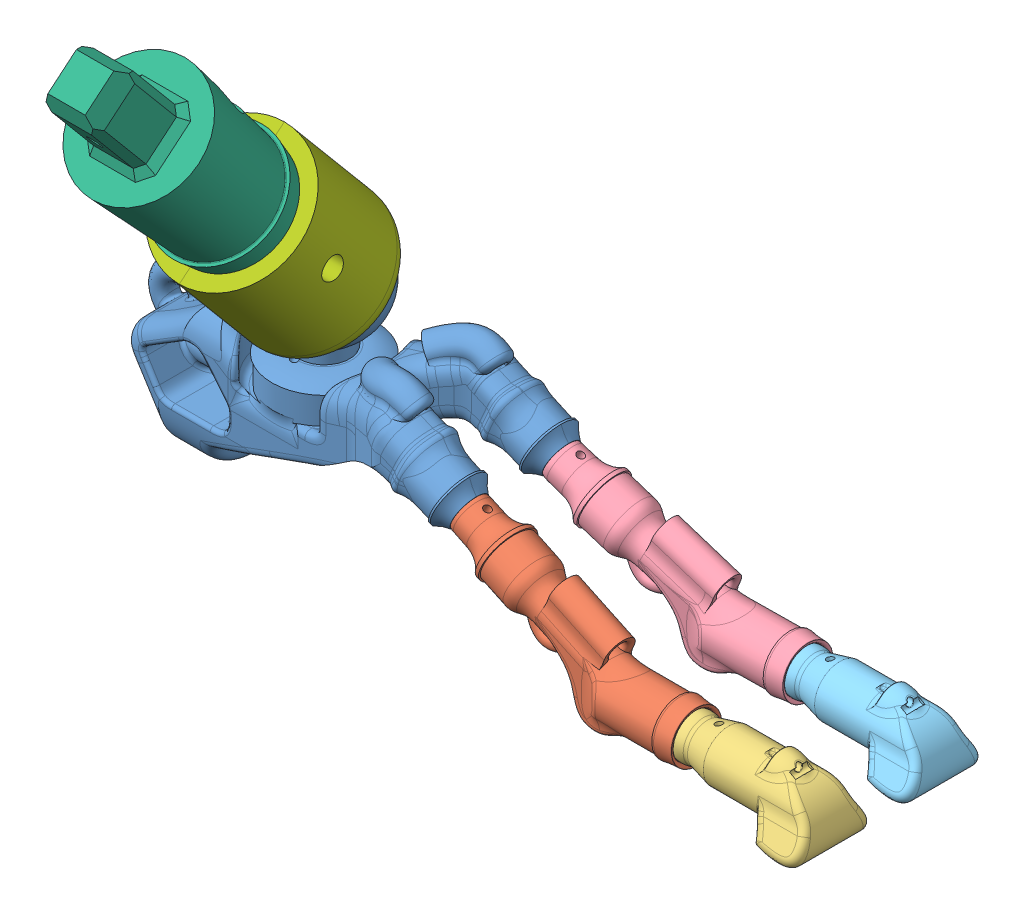
SolidWorks assembly Foot - side_to_side_motion, configuration Default. Lengths in mm.
Overall size (260.5 193.7 141.57).
8 component instances, 7 part files, 13 mates.
Components (placement in the parent):
- Talus - New-1: Talus - New [Default] at origin size (131.32 86.19 51)
- Metatarsals-1: Metatarsals [Default] at (104.0952 -44.3034 18.1531) x (-0.929116 0.366544 -0.048875) z (0.042994 -0.024198 -0.998782) size (95.04 30.95 38.02)
- Phalanges-1: Phalanges [Default] at (172.2396 -55.1541 19.5999) size (57.16 24.44 28.69)
- Metatarsals - Left side-1: Metatarsals - Left side [Default] at (104.1326 -44.2161 -17.9587) x (-0.930097 0.364252 0.047332) z (-0.050841 -0.000045 -0.998707) size (95.04 30.95 38.02)
- Phalanges - Left side-1: Phalanges - Left side [Default] at (172.3053 -54.9301 -19.5095) size (57.16 24.44 28.69)
- Tibial End-1: Tibial End [Default] x (0 -0.642788 0.766044) z (-1 0 0) size (42.45 113.08 48.21)
- Sleeve-4: Sleeve [Default] at (0 -0.115 -0.0965) x (-1 0 0) z (0 0.642788 -0.766044) size (26.67 50.7 48.26)
- Sleeve-5: Sleeve [Default] at (0 -0.115 -0.0965) x (1 0 0) z (0 -0.642788 0.766044) size (26.67 50.7 48.26)
Mates (geometry in assembly coordinates):
- Concentric1: concentric: sphere of Metatarsals-1; sphere of Talus - New-1
- Concentric2: concentric: sphere of Phalanges-1; sphere of Metatarsals-1
- Concentric3: concentric: sphere of Talus - New-1; sphere of Metatarsals - Left side-1
- Concentric4: concentric: sphere of Phalanges - Left side-1; sphere of Metatarsals - Left side-1
- Concentric5: concentric: cylinder of Tibial End-1 through (21.1996 25.1009 21.0621) axis (-1 0 0) radius 3.81; cylinder of Sleeve-5 through (38.608 25.1009 21.0621) axis (-1 0 0) radius 3.81
- Parallel3: parallel: plane of Tibial End-1 through (-9.525 96.0295 93.0123) normal (-1 0 0); plane of assembly through (0 0 0) normal (1 0 0)
- Concentric7: concentric: cone of Tibial End-1 through (0 0 0) axis (0 -0.766044 -0.642788); cone of Sleeve-5 through (0 0 0) axis (0 -0.766044 -0.642788)
- Parallel4: parallel: plane of Sleeve-4 through (0 -0.115 -0.0965) normal (1 0 0); plane of Sleeve-5 through (0 -0.115 -0.0965) normal (-1 0 0)
- Parallel5: parallel: cylinder of Sleeve-4 through (0 38.8001 32.5571) axis (0 -0.766044 -0.642788) radius 24.13; cylinder of Sleeve-5 through (0 38.8001 32.5571) axis (0 -0.766044 -0.642788) radius 24.13
- Concentric8: concentric: cylinder of Tibial End-1 through (21.1996 25.1009 21.0621) axis (-1 0 0) radius 3.81; cylinder of Sleeve-4 through (-38.608 25.1009 21.0621) axis (1 0 0) radius 3.81
- Coincident14: coincident: plane of Sleeve-4 through (0 -0.115 -0.0965) normal (1 0 0); plane of Sleeve-5 through (0 -0.115 -0.0965) normal (-1 0 0)
- LimitAngle1: limit planar angle = 3.839724 rad: plane of Tibial End-1 through (-9.525 108.2746 78.4192) normal (0 0.642788 -0.766044); plane of Talus - New-1 through (0 0 -17.78) normal (0 0 -1)
- Concentric10: concentric: sphere of Talus - New-1; sphere of Tibial End-1
